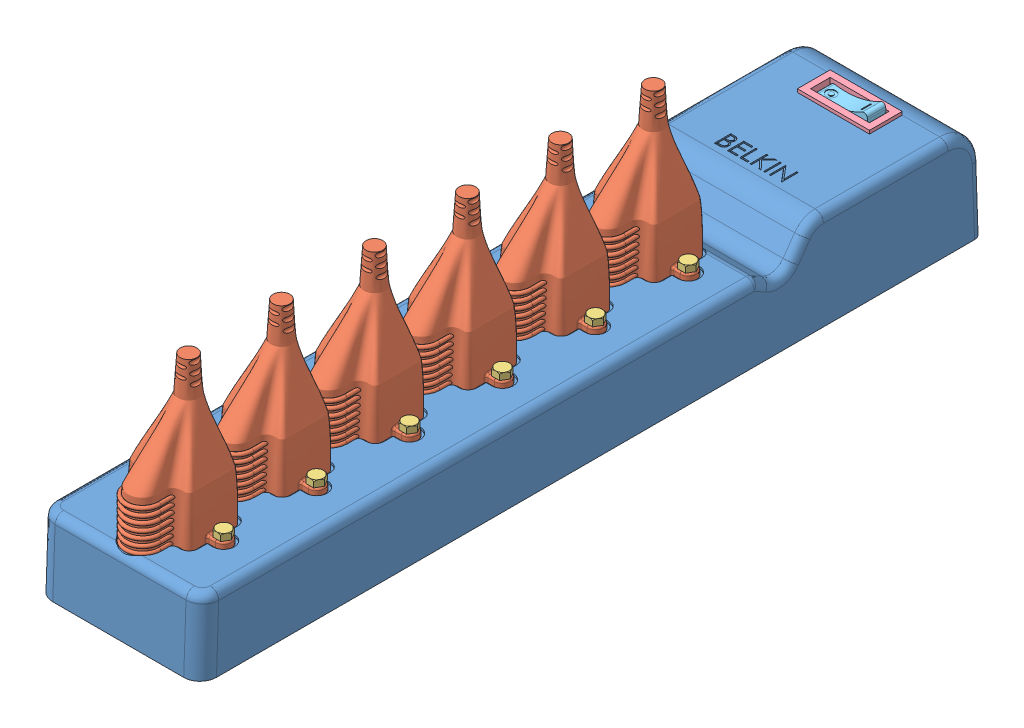
SolidWorks assembly Assem2, configuration Default. Lengths in mm.
Overall size (63.5 82.79 303.78).
22 component instances, 6 part files, 34 mates.
Components (placement in the parent):
- Power_Strip-1: Power_Strip [Default] at origin size (63.5 38.1 303.78)
- Plug-1: Plug [Default] at (0 27.9082 -53.4353) size (38.1 77.23 32.85)
- Screw-4: Screw [Default] at (-15.875 20.2883 -53.4353) size (6.1 12.71 5.28)
- Screw-3: Screw [Default] at (15.875 20.2883 -53.4353) size (6.1 12.71 5.28)
- Plug-13: Plug [Default] at (0 27.9082 -17.3673) size (38.1 77.23 32.85)
- Screw-16: Screw [Default] at (-15.875 20.2883 -17.3673) size (6.1 12.71 5.28)
- Screw-15: Screw [Default] at (15.875 20.2883 -17.3673) size (6.1 12.71 5.28)
- Plug-14: Plug [Default] at (0 27.9082 18.7007) size (38.1 77.23 32.85)
- Screw-18: Screw [Default] at (-15.875 20.2883 18.7007) size (6.1 12.71 5.28)
- Screw-17: Screw [Default] at (15.875 20.2883 18.7007) size (6.1 12.71 5.28)
- Plug-15: Plug [Default] at (0 27.9082 54.7687) size (38.1 77.23 32.85)
- Screw-20: Screw [Default] at (-15.875 20.2883 54.7687) size (6.1 12.71 5.28)
- Screw-19: Screw [Default] at (15.875 20.2883 54.7687) size (6.1 12.71 5.28)
- Plug-16: Plug [Default] at (0 27.9082 90.8367) size (38.1 77.23 32.85)
- Screw-22: Screw [Default] at (-15.875 20.2883 90.8367) size (6.1 12.71 5.28)
- Screw-21: Screw [Default] at (15.875 20.2883 90.8367) size (6.1 12.71 5.28)
- Plug-17: Plug [Default] at (0 27.9082 126.9047) size (38.1 77.23 32.85)
- Screw-24: Screw [Default] at (-15.875 20.2883 126.9047) size (6.1 12.71 5.28)
- Screw-23: Screw [Default] at (15.875 20.2883 126.9047) size (6.1 12.71 5.28)
- Switch_Housing-1: Switch_Housing [Default] at (0 33.02 -131.9473) x (0 0 1) z (-1 0 0) size (12.7 6.35 27.94)
- Switch_V2-2: Switch_V2 [Default] at (0 36.83 -131.9473) x (-0.984808 -0.173648 0) z (0 0 -1) size (21.59 4.51 7.11)
- Pin-4: Pin [Default] at (0 36.83 -131.3123) x (0 -1 0) z (-1 0 0) size (1.27 8.89 1.27)
Mates (geometry in assembly coordinates):
- Coincident1: coincident aligned: plane of Plug-1 through (0 27.9082 -53.4353) normal (1 0 0); plane of assembly through (0 0 0) normal (1 0 0)
- Distance2: distance = 0.7937 mm anti-aligned: plane of Power_Strip-1 through (31.75 28.702 150.8897) normal (0 1 0); plane of Plug-1 through (10.16 27.9082 -61.0553) normal (0 -1 0)
- Distance1: distance = 6.35 mm anti-aligned: plane of Plug-1 through (0 27.9082 -53.4353) normal (0 0 1); plane of assembly through (0 0 -47.0853) normal (0 0 -1)
- Coincident16: coincident anti-aligned: plane of Power_Strip-1 through (31.75 25.4 -63.2046) normal (1 0 0); plane of ? through (31.75 11.2213 -119.7378) normal (-1 0 0)
- ProfileCenter3: profile center = 0 mm anti-aligned: circle of Screw-4; circle of Plug-1
- Coincident23: coincident aligned: plane of Plug-13 through (0 27.9082 -17.3673) normal (1 0 0); plane of assembly through (0 0 0) normal (1 0 0)
- Distance15: distance = 0.7937 mm anti-aligned: plane of Power_Strip-1 through (31.75 28.702 150.8897) normal (0 1 0); plane of Plug-13 through (10.16 27.9082 -24.9873) normal (0 -1 0)
- Distance17: distance = 6.35 mm anti-aligned: plane of Plug-13 through (0 27.9082 -17.3673) normal (0 0 1); plane of assembly through (0 0 -11.0173) normal (0 0 -1)
- Coincident24: coincident aligned: plane of Plug-14 through (0 27.9082 18.7007) normal (1 0 0); plane of assembly through (0 0 0) normal (1 0 0)
- Distance18: distance = 0.7937 mm anti-aligned: plane of Power_Strip-1 through (31.75 28.702 150.8897) normal (0 1 0); plane of Plug-14 through (10.16 27.9082 11.0807) normal (0 -1 0)
- Distance19: distance = 6.35 mm anti-aligned: plane of Plug-14 through (0 27.9082 18.7007) normal (0 0 1); plane of assembly through (0 0 25.0507) normal (0 0 -1)
- Coincident25: coincident aligned: plane of Plug-15 through (0 27.9082 54.7687) normal (1 0 0); plane of assembly through (0 0 0) normal (1 0 0)
- Distance20: distance = 0.7937 mm anti-aligned: plane of Power_Strip-1 through (31.75 28.702 150.8897) normal (0 1 0); plane of Plug-15 through (10.16 27.9082 47.1487) normal (0 -1 0)
- Distance21: distance = 6.35 mm anti-aligned: plane of Plug-15 through (0 27.9082 54.7687) normal (0 0 1); plane of assembly through (0 0 61.1187) normal (0 0 -1)
- Coincident26: coincident aligned: plane of Plug-16 through (0 27.9082 90.8367) normal (1 0 0); plane of assembly through (0 0 0) normal (1 0 0)
- Distance22: distance = 0.7937 mm anti-aligned: plane of Power_Strip-1 through (31.75 28.702 150.8897) normal (0 1 0); plane of Plug-16 through (10.16 27.9082 83.2167) normal (0 -1 0)
- Distance23: distance = 6.35 mm anti-aligned: plane of Plug-16 through (0 27.9082 90.8367) normal (0 0 1); plane of assembly through (0 0 97.1867) normal (0 0 -1)
- Coincident27: coincident aligned: plane of Plug-17 through (0 27.9082 126.9047) normal (1 0 0); plane of assembly through (0 0 0) normal (1 0 0)
- Distance24: distance = 0.7937 mm anti-aligned: plane of Power_Strip-1 through (31.75 28.702 150.8897) normal (0 1 0); plane of Plug-17 through (10.16 27.9082 119.2847) normal (0 -1 0)
- Distance25: distance = 6.35 mm anti-aligned: plane of Plug-17 through (0 27.9082 126.9047) normal (0 0 1); plane of assembly through (0 0 133.2547) normal (0 0 -1)
- Coincident28: coincident aligned: plane of ? through (0 27.9082 37.455) normal (1 0 0); plane of assembly through (0 0 0) normal (1 0 0)
- Distance26: distance = 0.7937 mm anti-aligned: plane of Power_Strip-1 through (31.75 28.702 150.8897) normal (0 1 0); plane of ? through (10.16 27.9082 29.835) normal (0 -1 0)
- ProfileCenter15: profile center = 0 mm anti-aligned: circle of Screw-16; circle of Plug-13
- ProfileCenter17: profile center = 0 mm anti-aligned: circle of Screw-18; circle of Plug-14
- ProfileCenter19: profile center = 0 mm anti-aligned: circle of Screw-20; circle of Plug-15
- ProfileCenter21: profile center = 0 mm anti-aligned: circle of Screw-22; circle of Plug-16
- ProfileCenter23: profile center = 0 mm anti-aligned: circle of Screw-24; circle of Plug-17
- Coincident29: coincident anti-aligned: plane of Switch_Housing-1 through (0 33.02 -131.9473) normal (-1 0 0); plane of assembly through (0 0 0) normal (1 0 0)
- Coincident30: coincident anti-aligned: plane of Power_Strip-1 through (31.75 38.1 -138.2973) normal (0 1 0); plane of Switch_Housing-1 through (0 38.1 -131.9473) normal (0 -1 0)
- Coincident31: coincident aligned: line of Power_Strip-1 through (28.448 38.1 -138.2973) axis (-1 0 0); line of Switch_Housing-1 through (13.97 38.1 -138.2973) axis (-1 0 0)
- ProfileCenter24: profile center = 0 mm anti-aligned: circle of Pin-4; circle of Switch_Housing-1
- Concentric1: concentric anti-aligned: cylinder of Pin-4 through (0 36.83 -126.8673) axis (0 0 -1) radius 0.635; cylinder of Switch_V2-2 through (0 36.83 -135.5033) axis (0 0 1) radius 0.762
- Coincident32: coincident anti-aligned: plane of Switch_Housing-1 through (0 33.02 -131.9473) normal (0 0 1); plane of Switch_V2-2 through (0 36.83 -131.9473) normal (0 0 -1)
- LimitAngle1: limit planar angle = 1.396263 rad anti-aligned: plane of Switch_V2-2 through (0 36.83 -131.9473) normal (-0.984808 -0.173648 0); plane of Switch_Housing-1 through (0 39.37 -131.9473) normal (0 1 0)
